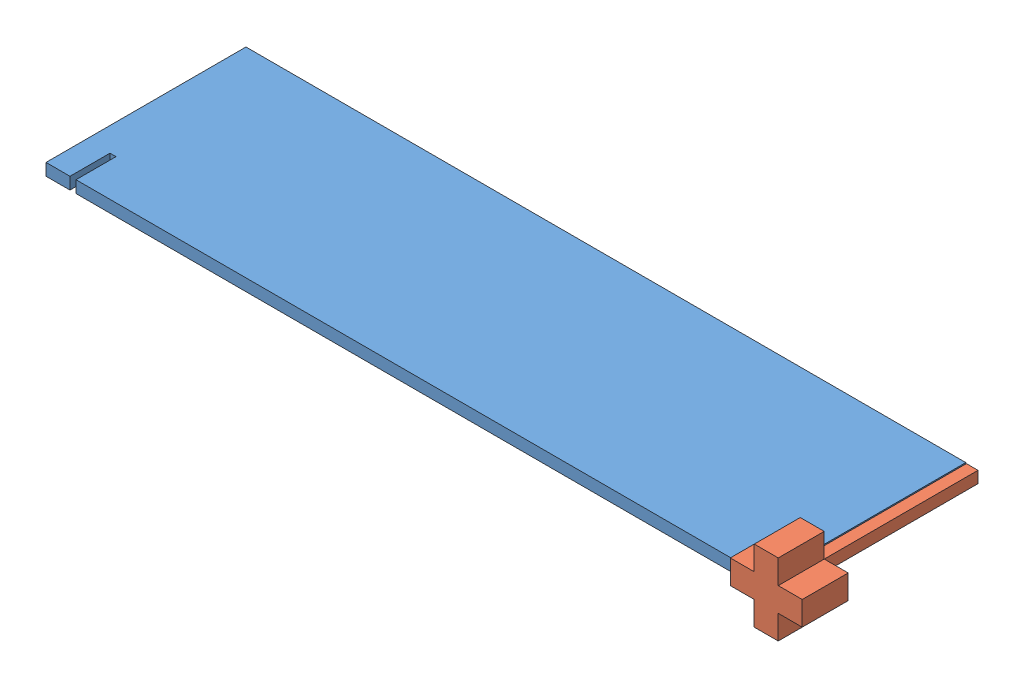
SolidWorks assembly maze, configuration Default. Lengths in mm.
Overall size (190.6 18 51.5).
2 component instances, 2 part files, 4 mates.
Components (placement in the parent):
- wall-1unit-1: wall-1unit [Default] x (-1 0 0) z (0 0 -1) size (180 3 50)
- corner-1: corner [cross] at (91.6 -0.1 26.5) x (1 0 0) z (0 1 0) size (18 51.5 18)
Mates (geometry in assembly coordinates):
- Coincident4: coincident anti-aligned: plane of wall-1unit-1 through (0 0 0) normal (-1 0 0)
- Coincident6: coincident anti-aligned: plane of wall-1unit-1 through (82.5 1.5 25) normal (0 0 1); plane of corner-1 through (91.6 -0.1 25) normal (0 0 -1)
- Coincident7: coincident anti-aligned: plane of wall-1unit-1 through (84 1.5 25) normal (-1 0 0); plane of corner-1 through (84 -1.7 15) normal (1 0 0)
- Coincident8: coincident anti-aligned: plane of wall-1unit-1 through (0 1.5 0) normal (0 1 0); plane of corner-1 through (84 1.5 15) normal (0 -1 0)
